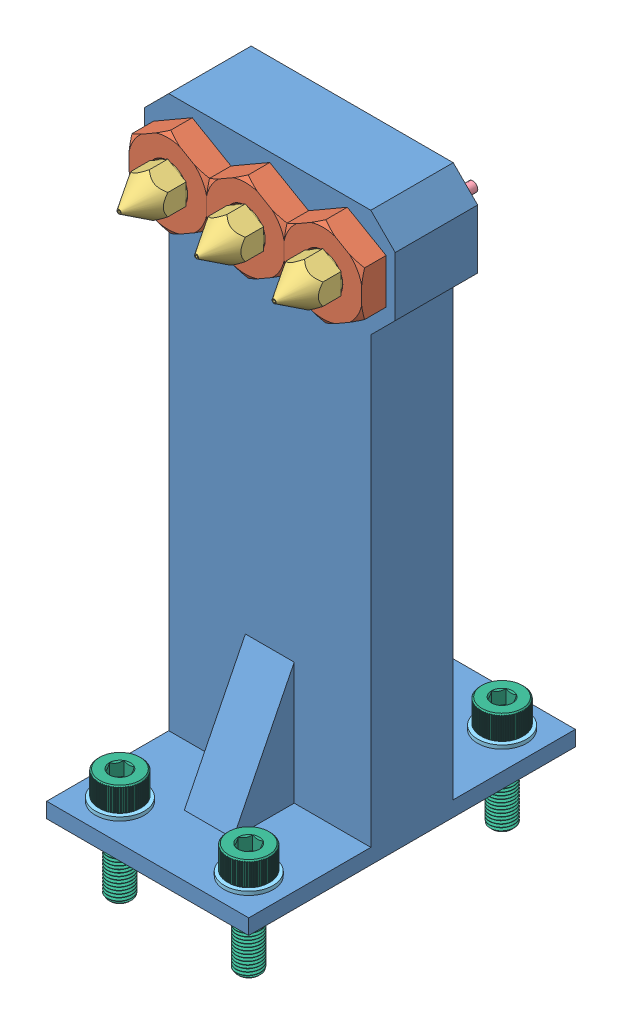
SolidWorks assembly 3 Nozzle Assembly, configuration Default. Lengths in mm.
Overall size (41.1 103.84 53.5).
21 component instances, 6 part files, 29 mates.
Components (placement in the parent):
- M22_3 Nozzle Holder-1: M22_3 Nozzle Holder [Default] at (16.7838 27.6748 26.5564) size (41.1 92.88 53.5)
- Custom Nozzle Assembly-1: Custom Nozzle Assembly [Default] at (16.7838 27.6748 42.5564) size (12.7 14.66 32.57)
  - M27_93020A775_LOW-STRENGTH STL HEX CPLG NUT-1: M27_93020A775_LOW-STRENGTH STL HEX CPLG NUT [93020A775] at origin size (12.7 14.66 16)
  - M20_Creality Brass Nozzle-1: M20_Creality Brass Nozzle [Default] at (0 0 8) size (6 7.32 13)
  - M21_5058K956_ALUMINUM LOW-PRESSURE BARBED TUBE FITTING-1: M21_5058K956_ALUMINUM LOW-PRESSURE BARBED TUBE FITTING [5058K956] at (0 0 -17.0319) x (0 0 -1) z (1 0 0) size (15.08 9.17 7.94)
- Custom Nozzle Assembly-2: Custom Nozzle Assembly [Default] at (4.0838 27.6748 42.5564) size (12.7 14.66 32.57)
  - M27_93020A775_LOW-STRENGTH STL HEX CPLG NUT-1: M27_93020A775_LOW-STRENGTH STL HEX CPLG NUT [93020A775] at origin size (12.7 14.66 16)
  - M20_Creality Brass Nozzle-1: M20_Creality Brass Nozzle [Default] at (0 0 8) size (6 7.32 13)
  - M21_5058K956_ALUMINUM LOW-PRESSURE BARBED TUBE FITTING-1: M21_5058K956_ALUMINUM LOW-PRESSURE BARBED TUBE FITTING [5058K956] at (0 0 -17.0319) x (0 0 -1) z (1 0 0) size (15.08 9.17 7.94)
- Custom Nozzle Assembly-3: Custom Nozzle Assembly [Default] at (29.4838 27.6748 42.5564) size (12.7 14.66 32.57)
  - M27_93020A775_LOW-STRENGTH STL HEX CPLG NUT-1: M27_93020A775_LOW-STRENGTH STL HEX CPLG NUT [93020A775] at origin size (12.7 14.66 16)
  - M20_Creality Brass Nozzle-1: M20_Creality Brass Nozzle [Default] at (0 0 8) size (6 7.32 13)
  - M21_5058K956_ALUMINUM LOW-PRESSURE BARBED TUBE FITTING-1: M21_5058K956_ALUMINUM LOW-PRESSURE BARBED TUBE FITTING [5058K956] at (0 0 -17.0319) x (0 0 -1) z (1 0 0) size (15.08 9.17 7.94)
- 98689A113_General Purpose 18-8 Stainless Steel Washer-1: 98689A113_General Purpose 18-8 Stainless Steel Washer [98689A113] at (6.2338 -53.2752 52.5564) x (0.996488 0 0.083731) z (0 -1 0) size (8 8 0.6)
- 98689A113_General Purpose 18-8 Stainless Steel Washer-2: 98689A113_General Purpose 18-8 Stainless Steel Washer [98689A113] at (6.2338 -53.2752 11.0564) x (0.996488 0 0.083731) z (0 -1 0) size (8 8 0.6)
- 98689A113_General Purpose 18-8 Stainless Steel Washer-3: 98689A113_General Purpose 18-8 Stainless Steel Washer [98689A113] at (27.3338 -53.2752 11.0564) x (0.996488 0 0.083731) z (0 -1 0) size (8 8 0.6)
- 98689A113_General Purpose 18-8 Stainless Steel Washer-4: 98689A113_General Purpose 18-8 Stainless Steel Washer [98689A113] at (27.3338 -53.2752 52.5564) x (0.996488 0 0.083731) z (0 -1 0) size (8 8 0.6)
- 90751A118_18-8 Stainless Steel Socket Head Screws-1: 90751A118_18-8 Stainless Steel Socket Head Screws [90751A118] at (6.2338 -53.2752 52.5564) x (0.866025 0 0.5) z (0 -1 0) size (7 7 18.23)
- 90751A118_18-8 Stainless Steel Socket Head Screws-3: 90751A118_18-8 Stainless Steel Socket Head Screws [90751A118] at (27.3338 -53.2752 11.0564) x (-0.866025 0 -0.5) z (0 -1 0) size (7 7 18.23)
- 90751A118_18-8 Stainless Steel Socket Head Screws-4: 90751A118_18-8 Stainless Steel Socket Head Screws [90751A118] at (6.2338 -53.2752 11.0564) x (-0.866025 0 -0.5) z (0 -1 0) size (7 7 18.23)
- 90751A118_18-8 Stainless Steel Socket Head Screws-5: 90751A118_18-8 Stainless Steel Socket Head Screws [90751A118] at (27.3338 -53.2752 52.5564) x (0.866025 0 0.5) z (0 -1 0) size (7 7 18.23)
Mates (geometry in assembly coordinates):
- Coincident1: coincident anti-aligned: plane of M22_3 Nozzle Holder-1 through (-2.2662 27.6748 38.5564) normal (1 0 0); plane of Custom Nozzle Assembly-2/93020A775_LOW-STRENGTH STL HEX CPLG NUT-1 through (-2.2662 31.341 26.5564) normal (-1 0 0)
- Coincident2: coincident anti-aligned: plane of M22_3 Nozzle Holder-1 through (16.7838 27.6748 38.5564) normal (-0.5 0.866025 0); plane of Custom Nozzle Assembly-2/93020A775_LOW-STRENGTH STL HEX CPLG NUT-1 through (4.0838 20.3425 26.5564) normal (0.5 -0.866025 0)
- Coincident3: coincident anti-aligned: plane of M22_3 Nozzle Holder-1 through (13.6088 33.1741 38.5564) normal (0.5 -0.866025 0); plane of Custom Nozzle Assembly-1/93020A775_LOW-STRENGTH STL HEX CPLG NUT-1 through (16.7838 35.0072 26.5564) normal (-0.5 0.866025 0)
- Coincident4: coincident anti-aligned: plane of M22_3 Nozzle Holder-1 through (13.6088 22.1756 38.5564) normal (0.5 0.866025 0); plane of Custom Nozzle Assembly-1/93020A775_LOW-STRENGTH STL HEX CPLG NUT-1 through (10.4338 24.0087 26.5564) normal (-0.5 -0.866025 0)
- Coincident5: coincident anti-aligned: plane of M22_3 Nozzle Holder-1 through (23.1338 38.6734 38.5564) normal (-0.5 -0.866025 0); plane of Custom Nozzle Assembly-3/93020A775_LOW-STRENGTH STL HEX CPLG NUT-1 through (35.8338 31.341 26.5564) normal (0.5 0.866025 0)
- Coincident6: coincident anti-aligned: plane of M22_3 Nozzle Holder-1 through (23.1338 16.6763 38.5564) normal (-0.5 0.866025 0); plane of Custom Nozzle Assembly-3/93020A775_LOW-STRENGTH STL HEX CPLG NUT-1 through (29.4838 20.3425 26.5564) normal (0.5 -0.866025 0)
- Coincident7: coincident anti-aligned: plane of M22_3 Nozzle Holder-1 through (16.7838 27.6748 26.5564) normal (0 0 1); plane of Custom Nozzle Assembly-3/93020A775_LOW-STRENGTH STL HEX CPLG NUT-1 through (22.9838 38.9332 26.5564) normal (0 0 -1)
- Coincident8: coincident anti-aligned: plane of M22_3 Nozzle Holder-1 through (16.7838 27.6748 26.5564) normal (0 0 1); plane of Custom Nozzle Assembly-1/93020A775_LOW-STRENGTH STL HEX CPLG NUT-1 through (10.2838 38.9332 26.5564) normal (0 0 -1)
- Coincident9: coincident anti-aligned: plane of M22_3 Nozzle Holder-1 through (16.7838 27.6748 26.5564) normal (0 0 1); plane of Custom Nozzle Assembly-2/93020A775_LOW-STRENGTH STL HEX CPLG NUT-1 through (-2.4162 38.9332 26.5564) normal (0 0 -1)
- Concentric1: concentric aligned: cylinder of M22_3 Nozzle Holder-1 through (6.2338 -56.3762 52.5564) axis (0 1 0) radius 2.25; cylinder of 98689A113_General Purpose 18-8 Stainless Steel Washer-1 through (6.2338 -53.8752 52.5564) axis (0 1 0) radius 2.15
- Coincident10: coincident anti-aligned: plane of M22_3 Nozzle Holder-1 through (16.7838 -53.8752 26.5564) normal (0 1 0); plane of 98689A113_General Purpose 18-8 Stainless Steel Washer-1 through (6.2338 -53.8752 52.5564) normal (0 -1 0)
- Coincident11: coincident anti-aligned: plane of M22_3 Nozzle Holder-1 through (16.7838 -53.8752 26.5564) normal (0 1 0); plane of 98689A113_General Purpose 18-8 Stainless Steel Washer-4 through (27.3338 -53.8752 52.5564) normal (0 -1 0)
- Concentric2: concentric aligned: cylinder of M22_3 Nozzle Holder-1 through (6.2338 -56.3762 11.0564) axis (0 1 0) radius 2.25; cylinder of 98689A113_General Purpose 18-8 Stainless Steel Washer-2 through (6.2338 -53.8752 11.0564) axis (0 1 0) radius 2.15
- Coincident13: coincident anti-aligned: plane of M22_3 Nozzle Holder-1 through (16.7838 -53.8752 26.5564) normal (0 1 0); plane of 98689A113_General Purpose 18-8 Stainless Steel Washer-2 through (6.2338 -53.8752 11.0564) normal (0 -1 0)
- Concentric3: concentric aligned: cylinder of M22_3 Nozzle Holder-1 through (27.3338 -56.3762 11.0564) axis (0 1 0) radius 2.25; cylinder of 98689A113_General Purpose 18-8 Stainless Steel Washer-3 through (27.3338 -53.8752 11.0564) axis (0 1 0) radius 2.15
- Coincident15: coincident anti-aligned: plane of M22_3 Nozzle Holder-1 through (16.7838 -53.8752 26.5564) normal (0 1 0); plane of 98689A113_General Purpose 18-8 Stainless Steel Washer-3 through (27.3338 -53.8752 11.0564) normal (0 -1 0)
- Concentric4: concentric aligned: cylinder of M22_3 Nozzle Holder-1 through (27.3338 -56.3762 52.5564) axis (0 1 0) radius 2.25; cylinder of 98689A113_General Purpose 18-8 Stainless Steel Washer-4 through (27.3338 -53.8752 52.5564) axis (0 1 0) radius 2.15
- Concentric5: concentric anti-aligned: circle of 98689A113_General Purpose 18-8 Stainless Steel Washer-1; circle of 90751A118_18-8 Stainless Steel Socket Head Screws-1
- Coincident17: coincident anti-aligned: plane of 98689A113_General Purpose 18-8 Stainless Steel Washer-1 through (6.2338 -53.2752 52.5564) normal (0 1 0); plane of 90751A118_18-8 Stainless Steel Socket Head Screws-1 through (4.5888 -53.2752 55.4056) normal (0 -1 0)
- Parallel1: parallel aligned: plane of M22_3 Nozzle Holder-1 through (33.3338 -53.8752 58.5564) normal (0 0 1); plane of 90751A118_18-8 Stainless Steel Socket Head Screws-1 through (7.0998 -51.5252 51.0564) normal (0 0 1)
- Concentric7: concentric anti-aligned: circle of 98689A113_General Purpose 18-8 Stainless Steel Washer-4; circle of 90751A118_18-8 Stainless Steel Socket Head Screws-5
- Coincident21: coincident anti-aligned: plane of 98689A113_General Purpose 18-8 Stainless Steel Washer-4 through (27.3338 -53.2752 52.5564) normal (0 1 0); plane of 90751A118_18-8 Stainless Steel Socket Head Screws-5 through (25.6888 -53.2752 55.4056) normal (0 -1 0)
- Parallel3: parallel anti-aligned: plane of M22_3 Nozzle Holder-1 through (33.3338 -53.8752 58.5564) normal (0 0 1); plane of 90751A118_18-8 Stainless Steel Socket Head Screws-5 through (26.4678 -51.5252 54.0564) normal (0 0 -1)
- Coincident24: coincident anti-aligned: plane of 98689A113_General Purpose 18-8 Stainless Steel Washer-3 through (27.3338 -53.2752 11.0564) normal (0 1 0); plane of 90751A118_18-8 Stainless Steel Socket Head Screws-3 through (28.9788 -53.2752 8.2072) normal (0 -1 0)
- Concentric8: concentric anti-aligned: circle of 98689A113_General Purpose 18-8 Stainless Steel Washer-3; circle of 90751A118_18-8 Stainless Steel Socket Head Screws-3
- Parallel4: parallel aligned: plane of M22_3 Nozzle Holder-1 through (33.3338 -53.8752 5.0564) normal (0 0 -1); plane of 90751A118_18-8 Stainless Steel Socket Head Screws-3 through (26.4678 -51.5252 12.5564) normal (0 0 -1)
- Concentric9: concentric aligned: circle of 98689A113_General Purpose 18-8 Stainless Steel Washer-2; circle of 90751A118_18-8 Stainless Steel Socket Head Screws-4
- Coincident27: coincident anti-aligned: plane of 98689A113_General Purpose 18-8 Stainless Steel Washer-2 through (6.2338 -53.2752 11.0564) normal (0 1 0); plane of 90751A118_18-8 Stainless Steel Socket Head Screws-4 through (7.8788 -53.2752 8.2072) normal (0 -1 0)
- Parallel5: parallel aligned: plane of M22_3 Nozzle Holder-1 through (33.3338 -53.8752 5.0564) normal (0 0 -1); plane of 90751A118_18-8 Stainless Steel Socket Head Screws-4 through (5.3678 -51.5252 12.5564) normal (0 0 -1)
